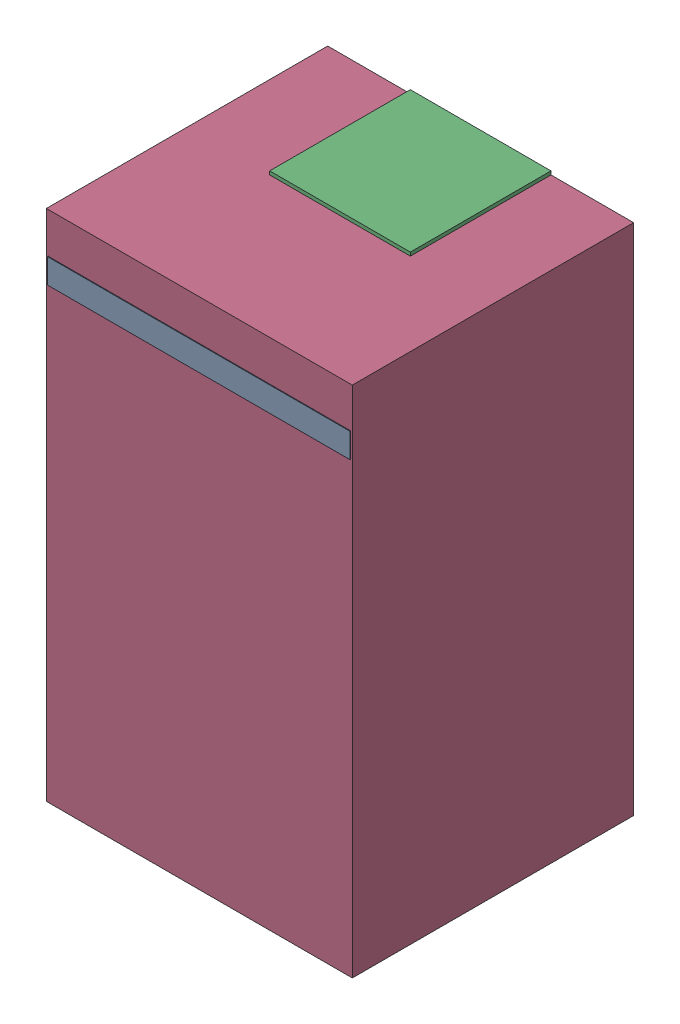
SolidWorks assembly C37, configuration Default. Lengths in mm.
Overall size (4.35 7.4 4.01).
8 component instances, 3 part files, 0 mates.
Components (placement in the parent):
- 870941440-1: 870941440 [Default] at (48.5132 35.3843 0) size (4.3 0.35 4.01)
  - Extruded_36-1: Extruded_36 [Default] at origin size (4.3 0.35 4.01)
- 870941600-1: 870941600 [Default] at (48.5132 28.8844 0) size (2 0.2 2)
  - Extruded_37-1: Extruded_37 [Default] at origin size (2 0.2 2)
- 870941600-2: 870941600 [Default] at (48.5132 36.0844 0) size (2 0.2 2)
  - Extruded_37-1: Extruded_37 [Default] at origin size (2 0.2 2)
- 870941760-1: 870941760 [Default] at (48.5133 32.4843 0) size (4.35 7.3 4)
  - Extruded_38-1: Extruded_38 [Default] at origin size (4.35 7.3 4)
